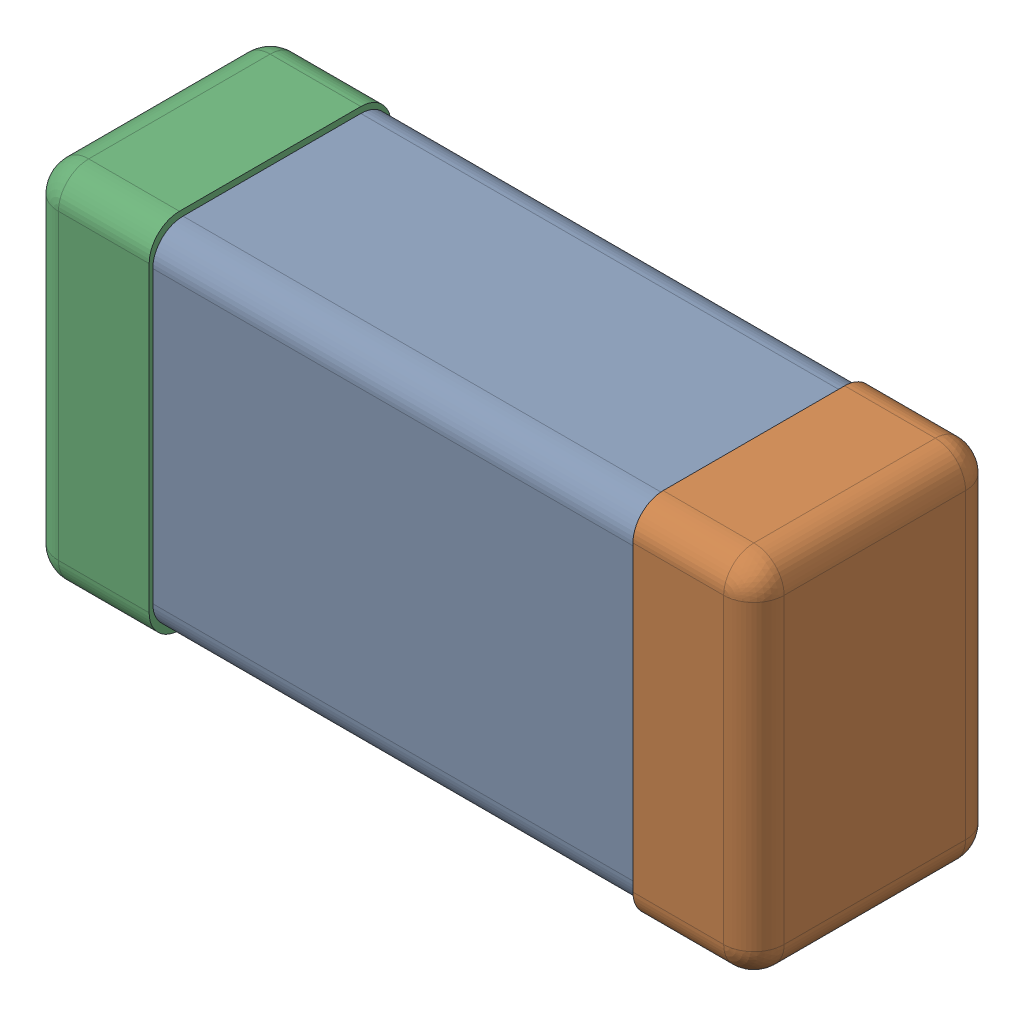
SolidWorks assembly C0201_020_2, configuration Standard. Lengths in mm.
Overall size (0.6 0.3 0.2).
4 component instances, 3 part files, 0 mates.
Components (placement in the parent):
- C0201_020_3-1: C0201_020_3 [Standard] at origin size (0.6 0.3 0.2)
  - Part 3_2-1: Part 3_2 [Standard] at (0 0 -7.3015) size (0.5 0.29 0.2)
  - Part 2_2-1: Part 2_2 [Standard] at (0 0 -7.3) size (0.1 0.3 0.2)
  - Part 1_2-1: Part 1_2 [Standard] at (0 0 -7.3) size (0.1 0.3 0.2)
